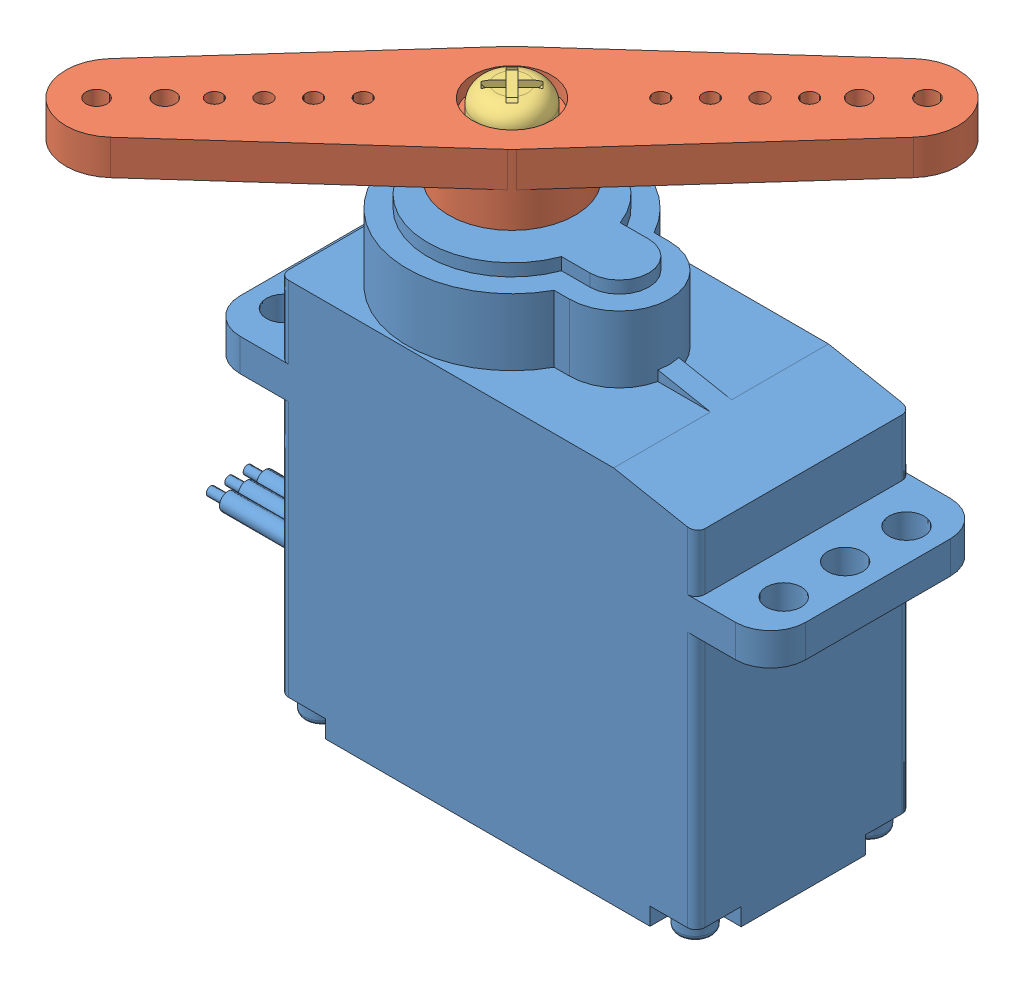
SolidWorks assembly SM-S2309S, configuration Default. Lengths in mm.
Overall size (37 31.58 31.68).
3 component instances, 3 part files, 6 mates.
Components (placement in the parent):
- SM-S2309S-1: SM-S2309S [Default] at origin size (37 29.3 12.25)
- SM-S2309S-Arm-1: SM-S2309S-Arm [Default] at (0 13.25 0) x (0.707107 0 -0.707107) z (0.707107 0 0.707107) size (37.6 4 7.2)
- SM-S2309S-Screw-1: SM-S2309S-Screw [Default] at (0 14.45 0) x (0.707107 0 -0.707107) z (0.707107 0 0.707107) size (3.8 6.73 3.8)
Mates (geometry in assembly coordinates):
- Coincident1: coincident: line of SM-S2309S-1 through (0 55 0) axis (0 -1 0); line of SM-S2309S-Arm-1 through (0 68.25 0) axis (0 -1 0)
- Coincident2: coincident: plane of SM-S2309S-1 through (1 13.7 0) normal (0 1 0); plane of SM-S2309S-Arm-1 through (0.6957 13.7 -0.8841) normal (0 -1 0)
- Coincident3: coincident: line of SM-S2309S-Arm-1 through (0 68.25 0) axis (0 -1 0); line of SM-S2309S-Screw-1 through (0 69.45 0) axis (0 -1 0)
- Coincident4: coincident: plane of SM-S2309S-Arm-1 through (1.3913 14.45 -1.7682) normal (0 1 0); plane of SM-S2309S-Screw-1 through (0.7266 14.45 -0.9234) normal (0 -1 0)
- Coincident5: coincident: plane of SM-S2309S-Arm-1; plane of SM-S2309S-Screw-1
- Angle1: planar angle = 0.785398 rad: plane of SM-S2309S-Arm-1 through (0 13.25 0) normal (0.707107 0 0.707107); plane of SM-S2309S-1 through (0 0 0) normal (0 0 1)
